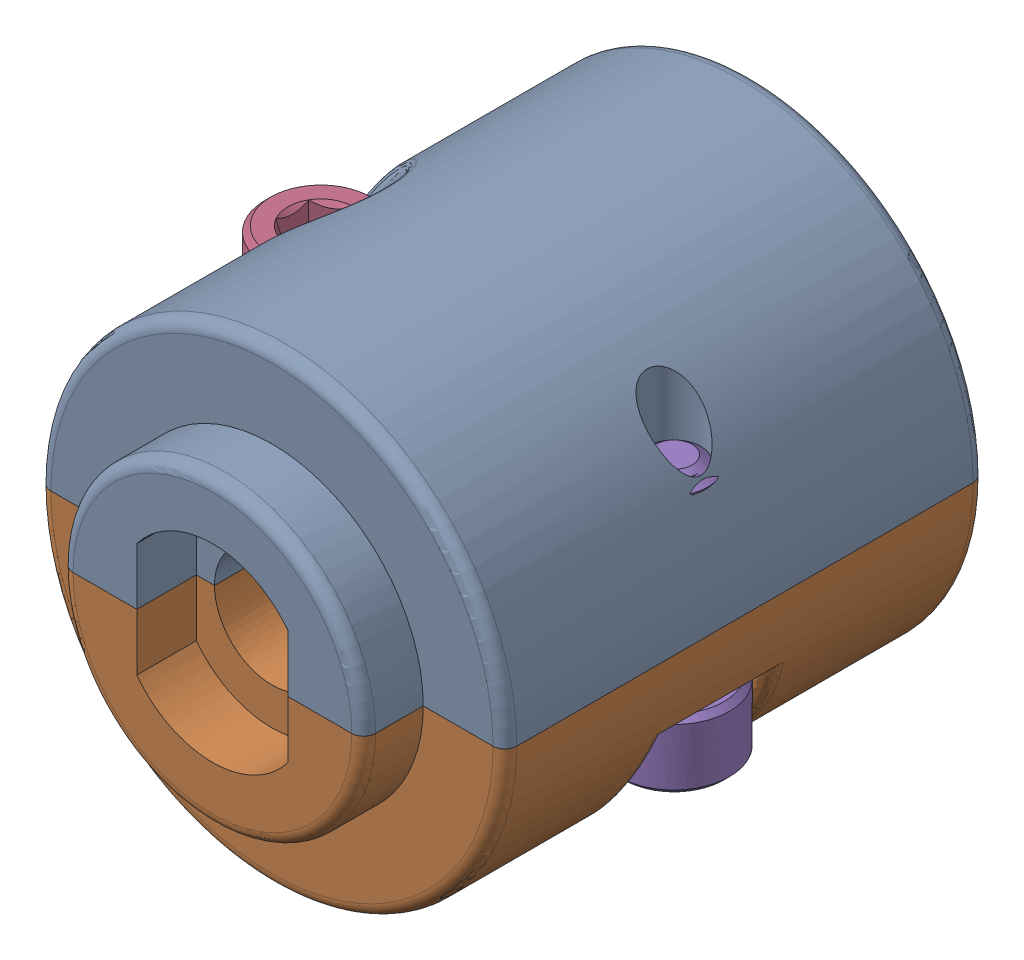
SolidWorks assembly 217-3195-200 Rev1_1, configuration Default. Lengths in mm.
Overall size (20.44 19.56 22.68).
5 component instances, 3 part files, 0 mates.
Components (placement in the parent):
- 217-3195-010 Rev1_1-1: 217-3195-010 Rev1_1 [Default] x (-1 0 0) z (0 0 1) size (19.61 11.78 22.68)
- 217-3195-010 Rev1_1-2: 217-3195-010 Rev1_1 [Default] at origin size (19.61 11.78 22.68)
- 217-2778-NCQ8A075-050M_1032_Nut_90545A111_1-1: 217-2778-NCQ8A075-050M_1032_Nut_90545A111_1 [Default] at (0 0 2.5527) x (-0.5 0.866025 0) z (0 0 1) size (9.53 11 3.39)
- 91251A107_91251A107-1: 91251A107_91251A107 [Default] at (-7.4168 -4.9375 -0.635) x (1 0 0) z (0 -1 0) size (4.65 4.65 10.79)
- 91251A107_91251A107-2: 91251A107_91251A107 [Default] at (7.4168 4.9375 -0.635) x (-0.837169 0 -0.546944) z (0 1 0) size (4.65 4.65 10.79)
